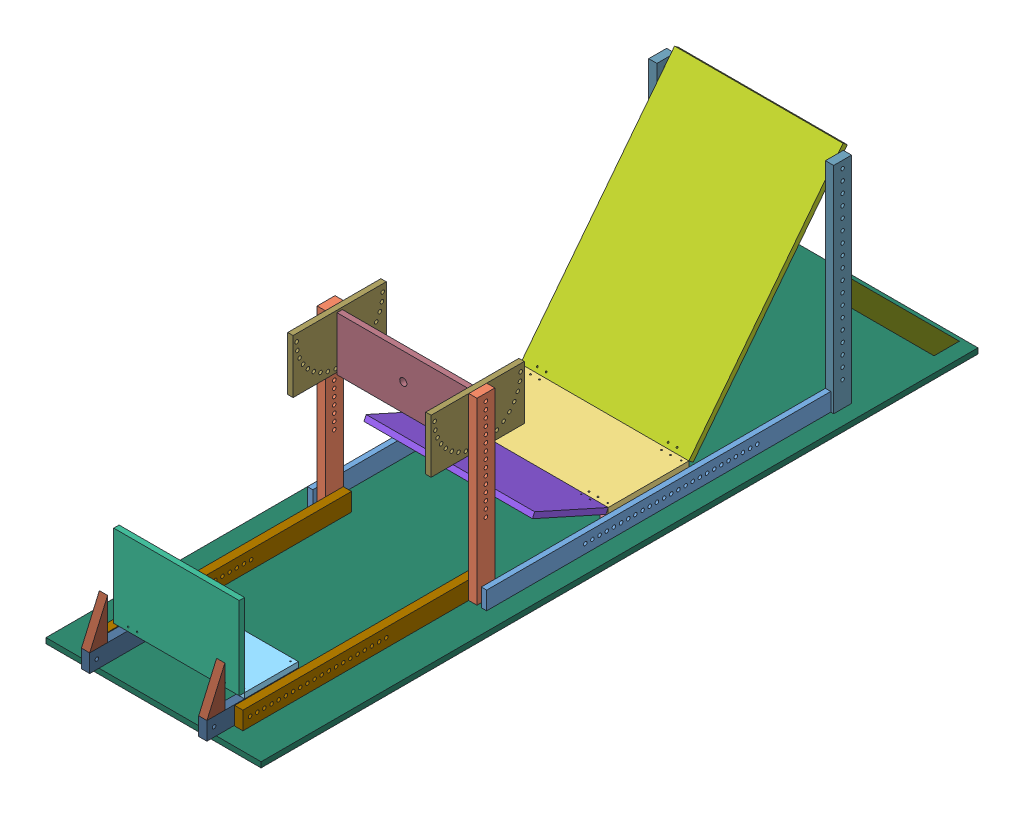
SolidWorks assembly mockchassis (refined), configuration Default. Lengths in mm.
Overall size (600 632.32 2026.08).
26 component instances, 17 part files, 65 mates.
Components (placement in the parent):
- base bar-1: base bar [Default] at (816.6926 1155.3719 1609.6049) size (15 50 960)
- Part5^mockchassis (refined)-1: Part5^mockchassis (refined) [Default] at (856.6926 1155.3719 1609.6049) x (0 0 -1) z (1 0 0) (virtual)
- base bar-3: base bar [Default] at (331.6926 1155.3719 1609.6049) size (15 50 960)
- supporting bar2-4: supporting bar2 [Default] at (358.6926 1380.3719 2064.6049) size (23 500 50)
- seat-1: seat [Default] at (581.6926 1180.3719 1622.9582) size (470 15 264.36)
- seat base bar-1: seat base bar [Default] at (793.6926 1155.3719 1622.9582) x (0 0 -1) z (1 0 0) size (225 50 23)
- seat base bar-2: seat base bar [Default] at (369.6926 1155.3719 1622.9582) x (0 0 1) z (-1 0 0) size (225 50 23)
- leg platform-1: leg platform [Default] at (581.6926 1180.3719 2614.9693) size (350 15 187.62)
- mock pedal-1: mock pedal [Default] at (581.6926 1310.3719 2689.9693) size (350 230 15)
- back plate-1: back plate [Default] at (581.6926 1462.3175 1283.599) x (1 0 0) z (0 0.614353 0.789031) size (470 700 15)
- seat rising-1: seat rising [Default] at (581.6926 1227.8323 1844.2128) x (1 0 0) z (0 0.41014 0.912023) size (470 15 225)
- supporting bar2-6: supporting bar2 [Default] at (781.6926 1380.3719 2064.6049) size (23 500 50)
- base bar2-1: base bar2 [Default] at (758.6926 1155.3719 2379.6049) size (23 50 680)
- base bar2-2: base bar2 [Default] at (381.6926 1155.3719 2379.6049) size (23 50 680)
- leg platform support-3: leg platform support [Default] at (429.6926 1155.3719 2667.4693) x (0 0 1) z (-1 0 0) size (255 50 23)
- leg platform support-5: leg platform support [Default] at (733.6926 1155.3719 2667.4693) x (0 0 -1) z (1 0 0) size (255 50 23)
- pedal box (adj)-4: pedal box (adj) [Default] at (406.6926 1204.4273 2704.9693) size (23 114 50)
- pedal box (adj)-5: pedal box (adj) [Default] at (733.6926 1204.4273 2704.9693) size (23 114 50)
- dashboard (adj.)-3: dashboard (adj.) [Default] at (381.6926 1555.3719 2064.6049) size (15 150 260)
- dashboard (adj.)-4: dashboard (adj.) [Default] at (766.6926 1555.3719 2064.6049) size (15 150 260)
- dashboard-2: dashboard [Default] at (581.6926 1549.3719 2057.1049) size (370 150 15)
- supporting bar-10: supporting bar [Default] at (839.6926 1430.3719 1104.6049) x (0 0 1) z (-1 0 0) size (50 600 23)
- supporting bar-11: supporting bar [Default] at (323.6926 1430.3719 1104.6049) x (0 0 -1) z (1 0 0) size (50 600 23)
- base-2: base [Default] at (581.6926 1115.3719 1768.8942) size (600 15 2000)
- back plate support-4: back plate support [Default] at (816.6926 1228.8658 1079.6049) x (0 0 -1) z (1 0 0) size (300.71 300.71 23)
- back plate support-5: back plate support [Default] at (323.6926 1228.8658 1079.6049) x (0 0 -1) z (1 0 0) size (300.71 300.71 23)
Mates (geometry in assembly coordinates):
- Coincident101: coincident aligned: plane of base bar-1 through (831.6926 1180.3719 2089.6049) normal (0 1 0); plane of base bar-3 through (346.6926 1180.3719 2089.6049) normal (0 1 0)
- Parallel1: parallel aligned: line of base bar-1 through (831.6926 1130.3719 1129.6049) axis (-1 0 0); line of base bar-3 through (346.6926 1130.3719 1129.6049) axis (-1 0 0)
- Distance8: distance = 470 mm: line of base bar-1 through (816.6926 1130.3719 1129.6049) axis (0 1 0); line of base bar-3 through (346.6926 1130.3719 1129.6049) axis (0 1 0)
- Coincident104: coincident anti-aligned: line of base bar-3 through (346.6926 1130.3719 2089.6049) axis (0 0 -1); line of seat base bar-2 through (346.6926 1130.3719 1510.4582) axis (0 0 1)
- Coincident105: coincident anti-aligned: plane of seat-1 through (581.6926 1180.3719 1622.9582) normal (0 -1 0); plane of seat base bar-2 through (346.6926 1180.3719 1510.4582) normal (0 1 0)
- Coincident106: coincident anti-aligned: plane of seat-1 through (581.6926 1180.3719 1622.9582) normal (0 -1 0); plane of seat base bar-1 through (816.6926 1180.3719 1735.4582) normal (0 1 0)
- Coincident107: coincident aligned: line of base bar-1 through (816.6926 1130.3719 2089.6049) axis (0 0 -1); line of seat base bar-1 through (816.6926 1130.3719 1735.4582) axis (0 0 -1)
- Coincident108: coincident aligned: line of seat-1 through (816.6926 1180.3719 1510.4582) axis (-1 0 0); line of seat base bar-1 through (816.6926 1180.3719 1510.4582) axis (-1 0 0)
- Coincident109: coincident aligned: line of seat-1 through (346.6926 1180.3719 1735.4582) axis (1 0 0); line of seat base bar-2 through (346.6926 1180.3719 1735.4582) axis (1 0 0)
- Coincident119: coincident anti-aligned: line of seat-1 through (346.6926 1180.3719 1510.4582) axis (0 0 1); line of seat base bar-2 through (346.6926 1180.3719 1735.4582) axis (0 0 -1)
- Coincident120: coincident anti-aligned: line of seat-1 through (346.6926 1195.3719 1735.4582) axis (1 0 0); line of seat rising-1 through (816.6926 1195.3719 1735.4582) axis (-1 0 0)
- Coincident121: coincident anti-aligned: line of seat-1 through (816.6926 1195.3719 1510.4582) axis (-1 0 0); line of back plate-1 through (346.6926 1195.3719 1510.4582) axis (1 0 0)
- Coincident122: coincident aligned: line of seat-1 through (816.6926 1180.3719 1510.4582) axis (-1 0 0); line of seat base bar-1 through (816.6926 1180.3719 1510.4582) axis (-1 0 0)
- Distance11: distance = 470 mm: line of base bar-3 through (346.6926 1180.3719 1129.6049) axis (0 0 1); line of base bar-1 through (816.6926 1180.3719 1129.6049) axis (0 0 1)
- Distance16: distance = 12 mm: line of supporting bar2-4 through (358.6926 1130.3719 2089.6049) axis (0 0 -1); line of base bar-3 through (346.6926 1130.3719 2089.6049) axis (0 0 -1)
- Coincident142: coincident aligned: plane of base bar-3 through (346.6926 1180.3719 2089.6049) normal (0 0 1); plane of supporting bar2-4 through (381.6926 1630.3719 2089.6049) normal (0 0 1)
- Distance20: distance = 12 mm: line of supporting bar2-6 through (804.6926 1130.3719 2089.6049) axis (0 0 -1); line of base bar-1 through (816.6926 1130.3719 2089.6049) axis (0 0 -1)
- Coincident158: coincident aligned: line of leg platform-1 through (406.6926 1195.3719 2689.9693) axis (1 0 0); line of mock pedal-1 through (406.6926 1195.3719 2689.9693) axis (1 0 0)
- Coincident175: coincident anti-aligned: plane of supporting bar2-6 through (781.6926 1380.3719 2064.6049) normal (-1 0 0); plane of base bar2-1 through (781.6926 1155.3719 2379.6049) normal (1 0 0)
- Coincident176: coincident aligned: plane of supporting bar2-6 through (804.6926 1630.3719 2039.6049) normal (0 0 -1); plane of base bar2-1 through (781.6926 1180.3719 2039.6049) normal (0 0 -1)
- Coincident177: coincident aligned: plane of supporting bar2-6 through (804.6926 1130.3719 2089.6049) normal (0 -1 0); plane of base bar2-1 through (781.6926 1130.3719 2719.6049) normal (0 -1 0)
- Coincident178: coincident anti-aligned: plane of supporting bar2-4 through (381.6926 1380.3719 2064.6049) normal (1 0 0); plane of base bar2-2 through (381.6926 1155.3719 2379.6049) normal (-1 0 0)
- Coincident179: coincident aligned: plane of supporting bar2-4 through (381.6926 1630.3719 2039.6049) normal (0 0 -1); plane of base bar2-2 through (404.6926 1180.3719 2039.6049) normal (0 0 -1)
- Coincident180: coincident aligned: plane of supporting bar2-4 through (381.6926 1130.3719 2089.6049) normal (0 -1 0); plane of base bar2-2 through (404.6926 1130.3719 2719.6049) normal (0 -1 0)
- Coincident195: coincident aligned: plane of seat-1 through (816.6926 1195.3719 1510.4582) normal (1 0 0); plane of seat rising-1 through (816.6926 1195.3719 1735.4582) normal (1 0 0)
- Coincident196: coincident aligned: plane of leg platform-1 through (406.6926 1195.3719 2539.9693) normal (-1 0 0); plane of mock pedal-1 through (406.6926 1425.3719 2704.9693) normal (-1 0 0)
- Coincident215: coincident aligned: plane of base bar-1 through (831.6926 1130.3719 2089.6049) normal (0 -1 0); plane of supporting bar2-6 through (804.6926 1130.3719 2089.6049) normal (0 -1 0)
- Coincident216: coincident anti-aligned: plane of leg platform-1 through (581.6926 1180.3719 2614.9693) normal (0 -1 0); plane of leg platform support-3 through (406.6926 1180.3719 2539.9693) normal (0 1 0)
- Coincident220: coincident aligned: plane of leg platform-1 through (406.6926 1195.3719 2539.9693) normal (0 0 -1); plane of leg platform support-3 through (406.6926 1180.3719 2539.9693) normal (0 0 -1)
- Coincident221: coincident anti-aligned: line of leg platform-1 through (406.6926 1180.3719 2539.9693) axis (0 0 1); line of leg platform support-3 through (406.6926 1180.3719 2794.9693) axis (0 0 -1)
- Coincident230: coincident aligned: line of base bar-1 through (831.6926 1130.3719 2089.6049) axis (-1 0 0); line of supporting bar2-6 through (804.6926 1130.3719 2089.6049) axis (-1 0 0)
- Coincident237: coincident anti-aligned: plane of leg platform-1 through (581.6926 1180.3719 2614.9693) normal (0 -1 0); plane of leg platform support-5 through (756.6926 1180.3719 2794.9693) normal (0 1 0)
- Coincident238: coincident anti-aligned: line of leg platform-1 through (756.6926 1180.3719 2689.9693) axis (0 0 -1); line of leg platform support-5 through (756.6926 1180.3719 2539.9693) axis (0 0 1)
- Coincident239: coincident aligned: plane of leg platform-1 through (406.6926 1195.3719 2539.9693) normal (0 0 -1); plane of leg platform support-5 through (756.6926 1180.3719 2539.9693) normal (0 0 -1)
- Coincident240: coincident aligned: plane of base bar2-1 through (781.6926 1130.3719 2719.6049) normal (0 -1 0); plane of leg platform support-5 through (756.6926 1130.3719 2794.9693) normal (0 -1 0)
- Distance23: distance = 2 mm: line of leg platform support-5 through (756.6926 1130.3719 2794.9693) axis (0 0 -1); line of base bar2-1 through (758.6926 1130.3719 2719.6049) axis (0 0 -1)
- Coincident285: coincident anti-aligned: plane of leg platform support-3 through (406.6926 1180.3719 2539.9693) normal (0 1 0); plane of pedal box (adj)-4 through (429.6926 1180.3719 2794.9693) normal (0 -1 0)
- Coincident286: coincident anti-aligned: line of leg platform support-3 through (406.6926 1180.3719 2794.9693) axis (1 0 0); line of pedal box (adj)-4 through (429.6926 1180.3719 2794.9693) axis (-1 0 0)
- Coincident287: coincident aligned: line of leg platform support-3 through (429.6926 1180.3719 2794.9693) axis (0 0 -1); line of pedal box (adj)-4 through (429.6926 1180.3719 2794.9693) axis (0 0 -1)
- Coincident288: coincident anti-aligned: plane of leg platform support-5 through (756.6926 1180.3719 2794.9693) normal (0 1 0); plane of pedal box (adj)-5 through (756.6926 1180.3719 2794.9693) normal (0 -1 0)
- Coincident289: coincident aligned: line of leg platform support-5 through (756.6926 1180.3719 2794.9693) axis (-1 0 0); line of pedal box (adj)-5 through (756.6926 1180.3719 2794.9693) axis (-1 0 0)
- Coincident290: coincident anti-aligned: line of leg platform support-5 through (756.6926 1180.3719 2539.9693) axis (0 0 1); line of pedal box (adj)-5 through (756.6926 1180.3719 2794.9693) axis (0 0 -1)
- Coincident291: coincident aligned: circle of dashboard (adj.)-3; circle of dashboard-2
- Coincident292: coincident anti-aligned: circle of dashboard (adj.)-4; circle of dashboard-2
- Parallel10: parallel aligned: plane of dashboard (adj.)-3 through (396.6926 1630.3719 2194.6049) normal (0 1 0); plane of dashboard-2 through (396.6926 1624.3719 2072.1049) normal (0 1 0)
- Parallel11: parallel aligned: plane of dashboard (adj.)-4 through (781.6926 1630.3719 2194.6049) normal (0 1 0); plane of dashboard-2 through (396.6926 1624.3719 2072.1049) normal (0 1 0)
- Perpendicular2: perpendicular: plane of dashboard (adj.)-3 through (396.6926 1555.3719 2064.6049) normal (1 0 0); plane of dashboard-2 through (581.6926 1549.3719 2072.1049) normal (0 0 1)
- Perpendicular3: perpendicular: plane of dashboard (adj.)-4 through (766.6926 1555.3719 2064.6049) normal (-1 0 0); plane of dashboard-2 through (581.6926 1549.3719 2072.1049) normal (0 0 1)
- Coincident297: coincident anti-aligned: circle of supporting bar2-4; circle of dashboard (adj.)-3
- Coincident298: coincident anti-aligned: plane of base bar-3 through (346.6926 1155.3719 1609.6049) normal (1 0 0); plane of seat base bar-2 through (346.6926 1155.3719 1622.9582) normal (-1 0 0)
- Coincident299: coincident anti-aligned: plane of base bar-1 through (831.6926 1180.3719 1129.6049) normal (0 0 -1); plane of supporting bar-10 through (816.6926 1730.3719 1129.6049) normal (0 0 1)
- Coincident300: coincident aligned: line of base bar-1 through (816.6926 1130.3719 1129.6049) axis (0 1 0); line of supporting bar-10 through (816.6926 1130.3719 1129.6049) axis (0 1 0)
- Coincident301: coincident aligned: plane of base bar-1 through (831.6926 1130.3719 2089.6049) normal (0 -1 0); plane of supporting bar-10 through (816.6926 1130.3719 1079.6049) normal (0 -1 0)
- Coincident302: coincident anti-aligned: plane of base bar-3 through (346.6926 1180.3719 1129.6049) normal (0 0 -1); plane of supporting bar-11 through (346.6926 1730.3719 1129.6049) normal (0 0 1)
- Coincident303: coincident anti-aligned: line of base bar-3 through (346.6926 1130.3719 1129.6049) axis (0 1 0); line of supporting bar-11 through (346.6926 1730.3719 1129.6049) axis (0 -1 0)
- Coincident304: coincident aligned: plane of base bar-3 through (346.6926 1130.3719 2089.6049) normal (0 -1 0); plane of supporting bar-11 through (346.6926 1130.3719 1129.6049) normal (0 -1 0)
- Coincident307: coincident anti-aligned: plane of base bar-3 through (346.6926 1130.3719 2089.6049) normal (0 -1 0); plane of base-2 through (581.6926 1130.3719 1768.8942) normal (0 1 0)
- Coincident310: coincident anti-aligned: plane of supporting bar-10 through (816.6926 1730.3719 1079.6049) normal (0 0 -1); plane of back plate support-4 through (839.6926 1431.0826 1079.6049) normal (0 0 1)
- Coincident311: coincident aligned: line of supporting bar-10 through (839.6926 1730.3719 1079.6049) axis (0 -1 0); line of back plate support-4 through (839.6926 1431.0826 1079.6049) axis (0 -1 0)
- Coincident312: coincident anti-aligned: plane of base-2 through (581.6926 1130.3719 1768.8942) normal (0 1 0); plane of back plate support-4 through (839.6926 1130.3719 849.6049) normal (0 -1 0)
- Coincident313: coincident anti-aligned: plane of supporting bar-11 through (346.6926 1730.3719 1079.6049) normal (0 0 -1); plane of back plate support-5 through (346.6926 1431.0826 1079.6049) normal (0 0 1)
- Coincident314: coincident anti-aligned: plane of base-2 through (581.6926 1130.3719 1768.8942) normal (0 1 0); plane of back plate support-5 through (346.6926 1130.3719 849.6049) normal (0 -1 0)
- Coincident315: coincident anti-aligned: line of supporting bar-11 through (323.6926 1130.3719 1079.6049) axis (0 1 0); line of back plate support-5 through (323.6926 1431.0826 1079.6049) axis (0 -1 0)
- Distance24: distance = 42 mm: line of base-2 through (881.6926 1130.3719 2768.8942) axis (0 0 -1); line of supporting bar-10 through (839.6926 1130.3719 1079.6049) axis (0 0 1)
- Distance25: distance = 10 mm: line of base-2 through (881.6926 1130.3719 768.8942) axis (-1 0 0); line of back plate support-4 through (839.6926 1130.3719 778.8942) axis (-1 0 0)
